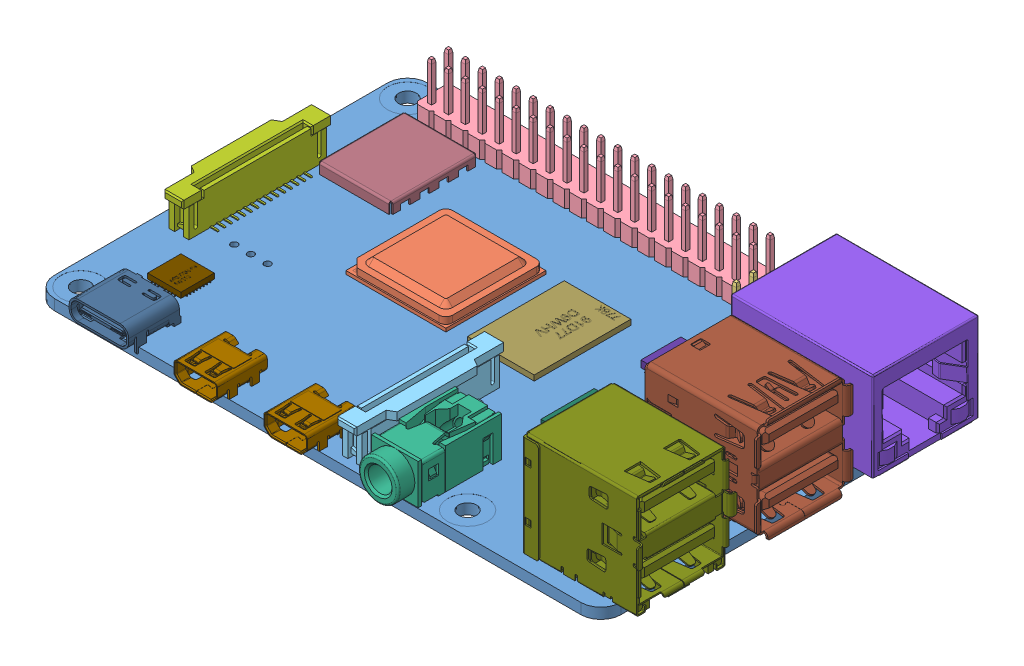
SolidWorks assembly RP_4_DUMMY, configuration Default. Lengths in mm.
Overall size (88.99 19.9 58.4).
19 component instances, 18 part files, 0 mates.
Components (placement in the parent):
- PCB, RPi4ModelB-1-1: PCB, RPi4ModelB-1 [По умолчанию] at origin size (85 1.6 56)
- Broadcom BCM2711B0 CPU, RPi4ModelB-1-1: Broadcom BCM2711B0 CPU, RPi4ModelB-1 [По умолчанию] at (-13.25 0.8 -4.5) size (15 2.3 15)
- 2.54 mm DUPONT MALE PIN HEADER, POE, 2X2, RPi4ModelB-1-1: 2.54 mm DUPONT MALE PIN HEADER, POE, 2X2, RPi4ModelB-1 [По умолчанию] at (19 0.8 -18.36) size (5.08 11.3 5.08)
- 2.54 mm DUPONT MALE PIN HEADER, IO, 2X20, RPi4ModelB-1-1: 2.54 mm DUPONT MALE PIN HEADER, IO, 2X20, RPi4ModelB-1 [По умолчанию] at (-10 0.8 -24.5) size (50.8 11.3 5.08)
- Camera Connector, RPi4ModelB-1-1: Camera Connector, RPi4ModelB-1 [По умолчанию] at (4 0.8 16.5) x (0 0 -1) z (1 0 0) size (22.4 5.68 5.07)
- Microphone Plug, RPi4ModelB-1-1: Microphone Plug, RPi4ModelB-1 [По умолчанию] at (11.5 0.8 21.65) size (7.23 7.55 15)
- Display Connector, RPi4ModelB-1-1: Display Connector, RPi4ModelB-1 [По умолчанию] at (-38.5 0.8 0) x (0 0 1) z (-1 0 0) size (22.4 5.68 5.07)
- Gigabit Ethernet Port, RPi4ModelB-1-1: Gigabit Ethernet Port, RPi4ModelB-1 [По умолчанию] at (45.5 7.55 -17.75) x (0 0 -1) z (1 0 0) size (16.2 17.24 21.64)
- Female Micro HDMI Connector, RPi4ModelB-1-1: Female Micro HDMI Connector, RPi4ModelB-1 [По умолчанию] at (-3 0.8 27.3875) size (6.5 3.51 7.5)
- Female Micro HDMI Connector, RPi4ModelB-1-2: Female Micro HDMI Connector, RPi4ModelB-1 [По умолчанию] at (-16.5 0.8 27.3875) size (6.5 3.51 7.5)
- Female USB Type C Connector, RPi4ModelB-1-1: Female USB Type C Connector, RPi4ModelB-1 [По умолчанию] at (-31.3 0.8 26.5419) size (8.94 3.96 7.9)
- 2X USB3.0 PORTS, RPi4ModelB-1-1: 2X USB3.0 PORTS, RPi4ModelB-1 [По умолчанию] at (37.07 0.8 1) size (17.47 19.41 15.68)
- 91D77 D9WHV 778K, 4 GB LPDDR4 SDRAM, RPi4ModelB-1-1: 91D77 D9WHV 778K, 4 GB LPDDR4 SDRAM, RPi4ModelB-1 [По умолчанию] at (2.25 0.8 -4.5) size (10 0.8 14.5)
- Cypress CYW43455 Wireless Module Cover, RPi4ModelB-1-1: Cypress CYW43455 Wireless Module Cover, RPi4ModelB-1 [По умолчанию] at (-30.5 0.8 -14.5) size (11 1.6 13)
- SD Card Slot, RPi4ModelB-1-1: SD Card Slot, RPi4ModelB-1 [По умолчанию] at (-35.3 -0.8 0) x (0 0 -1) z (-1 0 0) size (11.95 1.45 11.4)
- VIA VL805 PCIe USB 3.0 controller, RPi4ModelB-1-1: VIA VL805 PCIe USB 3.0 controller, RPi4ModelB-1 [По умолчанию] at (17.5 0.8 4) size (8.8 0.8 8.8)
- 2X USB2.0 PORTS, RPi4ModelB-1-1: 2X USB2.0 PORTS, RPi4ModelB-1 [По умолчанию] at (37.065 0.65 19) size (17.87 19.16 15.33)
- Broadcom BCM54213PE Gigabit Ethernet Transceiver, RPi4ModelB-1-1: Broadcom BCM54213PE Gigabit Ethernet Transceiver, RPi4ModelB-1 [По умолчанию] at (16.5 0.8 -10) size (6.8 1 6.8)
- MxL7704 Universal PMIC, RPi4ModelB-1-1: MxL7704 Universal PMIC, RPi4ModelB-1 [По умолчанию] at (-32.5 0.8 16) size (5.4 0.8 5.4)
